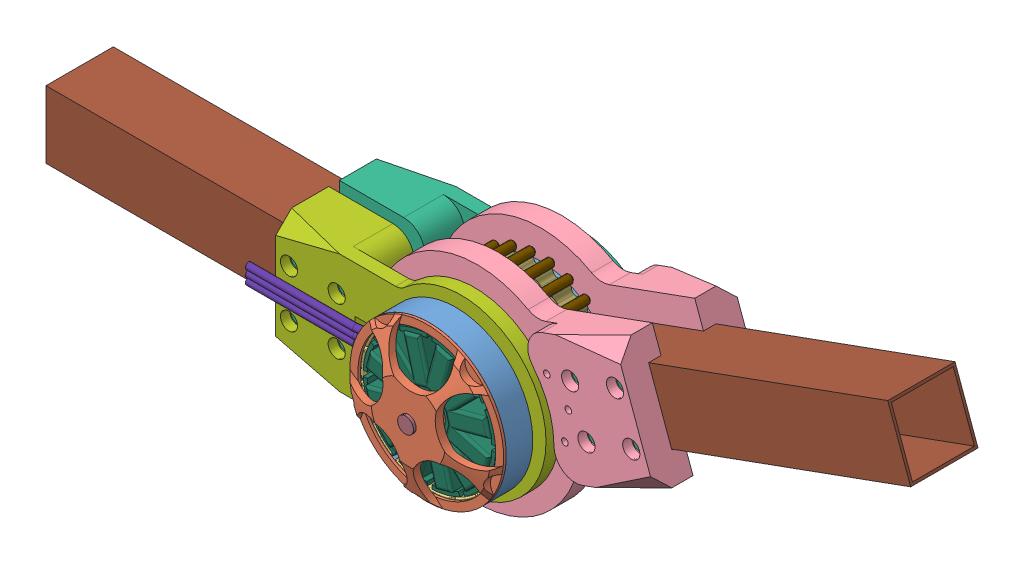
SolidWorks assembly hackaday, configuration Default. Lengths in mm.
Overall size (326.32 118.67 77).
127 component instances, 29 part files, 0 mates.
Components (placement in the parent):
- hackaday.stp-1: hackaday.stp [Default] at origin size (326.32 118.67 77)
  - 5008 motor.stp-1: 5008 motor.stp [Default] at (-7.1087 -103.7283 -19.7066) x (-0.351498 -0.936188 0) z (-0.936188 0.351498 0) size (59.12 18.06 59.12)
    - motor 5008 flux.stp-1: motor 5008 flux.stp [Default] at (33.74 9.1866 34) x (1 0 0) z (0 1 0) size (58 58 10)
    - motor 5008 top.stp-1: motor 5008 top.stp [Default] at (33.74 19.1866 34) size (59.12 8.62 59.12)
    - magnet 5008.stp-1: magnet 5008.stp [Default] at (33.74 19.1866 34) x (0.92388 0 0.382683) z (0 -1 0) size (10.37 4.02 10)
    - magnet 5008.stp-2: magnet 5008.stp [Default] at (33.74 19.1866 34) x (0.666347 0 0.745642) z (0 -1 0) size (10.37 4.02 10)
    - magnet 5008.stp-3: magnet 5008.stp [Default] at (33.74 19.1866 34) x (0.276836 0 0.960917) z (0 -1 0) size (10.37 4.02 10)
    - magnet 5008.stp-4: magnet 5008.stp [Default] at (33.74 19.1866 34) x (-0.167506 0 0.985871) z (0 -1 0) size (10.37 4.02 10)
    - magnet 5008.stp-5: magnet 5008.stp [Default] at (33.74 19.1866 34) x (-0.578671 0 0.815561) z (0 -1 0) size (10.37 4.02 10)
    - magnet 5008.stp-6: magnet 5008.stp [Default] at (33.74 19.1866 34) x (-0.875223 0 0.483719) z (0 -1 0) size (10.37 4.02 10)
    - magnet 5008.stp-7: magnet 5008.stp [Default] at (33.74 19.1866 34) x (-0.998427 0 0.05607) z (0 -1 0) size (10.37 4.02 10)
    - magnet 5008.stp-8: magnet 5008.stp [Default] at (33.74 19.1866 34) x (-0.92388 0 -0.382683) z (0 -1 0) size (10.37 4.02 10)
    - magnet 5008.stp-9: magnet 5008.stp [Default] at (33.74 19.1866 34) x (-0.666347 0 -0.745642) z (0 -1 0) size (10.37 4.02 10)
    - magnet 5008.stp-10: magnet 5008.stp [Default] at (33.74 19.1866 34) x (-0.276836 0 -0.960917) z (0 -1 0) size (10.37 4.02 10)
    - magnet 5008.stp-11: magnet 5008.stp [Default] at (33.74 19.1866 34) x (0.167506 0 -0.985871) z (0 -1 0) size (10.37 4.02 10)
    - magnet 5008.stp-12: magnet 5008.stp [Default] at (33.74 19.1866 34) x (0.578671 0 -0.815561) z (0 -1 0) size (10.37 4.02 10)
    - magnet 5008.stp-13: magnet 5008.stp [Default] at (33.74 19.1866 34) x (0.875223 0 -0.483719) z (0 -1 0) size (10.37 4.02 10)
    - magnet 5008.stp-14: magnet 5008.stp [Default] at (33.74 19.1866 34) x (0.998427 0 -0.05607) z (0 -1 0) size (10.37 4.02 10)
  - 6809_joint_out.stp-1: 6809_joint_out.stp [Default] at (-50.7987 -123.3644 -43.52) x (-0.34114 0.940012 0) z (0 0 -1) size (78 109 14)
  - 6809_joint_out.stp-2: 6809_joint_out.stp [Default] at (-50.7987 -123.3644 -25.52) x (0.34114 -0.940012 0) z (0 0 1) size (78 109 14)
  - 58x45x7_bearing.stp-1: 58x45x7_bearing.stp [Default] at (-50.7987 -123.3644 -18.52) x (1 0 0) z (0 0 -1) size (58 58 7)
  - 58x45x7_bearing.stp-2: 58x45x7_bearing.stp [Default] at (-50.7987 -123.3644 -43.52) x (1 0 0) z (0 0 -1) size (58 58 7)
  - encoder in 6809.stp-1: encoder in 6809.stp [Default] at (-50.7987 -123.3644 -42.52) x (1 0 0) z (0 0 -1) size (102 64 20)
  - motor in 6809.stp-1: motor in 6809.stp [Default] at (-50.7987 -123.3644 -26.52) size (102 64 20)
  - outer_bearing_holder.stp-1: outer_bearing_holder.stp [Default] at (-50.7987 -123.3644 -56.52) x (0 -1 0) z (0 0 -1) size (34 22 8)
  - enc_pcb.stp-1: enc_pcb.stp [Default] at (-50.7987 -123.3644 -53.52) x (1 0 0) z (0 0 -1) size (27 16 1.8)
  - enc_pcb.stp-2: enc_pcb.stp [Default] at (-50.7987 -123.3644 -58.32) x (1 0 0) z (0 0 -1) size (27 16 1.8)
  - magnet_holder.stp-1: magnet_holder.stp [Default] at (-50.7987 -123.3644 -65.52) x (0.34114 -0.940012 0) z (0 0 1) size (30 55 12)
  - bar25x25.stp-1: bar25x25.stp [Default] at (-11.3693 -108.8955 -34.52) x (0 0 -1) z (0.940012 0.34114 0) size (25.4 25.4 124)
  - bar25x25.stp-2: bar25x25.stp [Default] at (-92.7987 -123.2644 -34.52) x (0 0 1) z (-1 0 0) size (25.4 25.4 124)
  - inner_ring_25l.stp-1: inner_ring_25l.stp [Default] at (-50.111 -124.0904 -42.02) x (0.330465 0.943818 0) z (0 0 1) size (59.09 59.19 7)
  - inner_ring_25l.stp-2: inner_ring_25l.stp [Default] at (-51.4863 -122.6384 -27.02) x (-0.947128 0.320857 0) z (0 0 -1) size (59.09 59.19 7)
  - shaft_6mm.stp-1: shaft_6mm.stp [Default] at (-50.7987 -123.3644 -49.52) x (-0.834633 0.550807 0) z (0 0 1) size (6 6 58)
  - encoder_bearing_holder-45.stp-1: encoder_bearing_holder-45.stp [Default] at (-50.7987 -123.3644 -42.52) x (-1 0 0) z (0 0 -1) size (19 23.63 4)
  - motor 5008 stator.stp-1: motor 5008 stator.stp [Default] at (-50.7987 -123.3644 -0.52) x (1 0 0) z (0 0 -1) size (54.25 54.25 20.31)
  - sensor_cable.stp-1: sensor_cable.stp [Default] at (-130.7987 -126.7353 -57.155) x (1 0 0) z (0 1 0) size (67.53 3.96 7.65)
  - motor cable.stp-1: motor cable.stp [Default] at (-75.7987 -120.692 -13.5933) x (1 0 0) z (0 -1 0) size (54.18 4.8 7.51)
  - outer_pins.stp-1: outer_pins.stp [Default] at (-40.4962 -151.7528 -49.52) x (0.901282 0.433233 0) z (0 0 1) size (3.2 3.2 30)
  - outer_pins.stp-2: outer_pins.stp [Default] at (-47.5894 -153.3934 -49.52) x (0.978772 0.204953 0) z (0 0 1) size (3.2 3.2 30)
  - outer_pins.stp-3: outer_pins.stp [Default] at (-54.8691 -153.2888 -49.52) x (0.999379 -0.035238 0) z (0 0 1) size (3.2 3.2 30)
  - outer_pins.stp-4: outer_pins.stp [Default] at (-61.9122 -151.4452 -49.52) x (0.961906 -0.273381 0) z (0 0 1) size (3.2 3.2 30)
  - outer_pins.stp-5: outer_pins.stp [Default] at (-68.3094 -147.9696 -49.52) x (0.86853 -0.495637 0) z (0 0 1) size (3.2 3.2 30)
  - outer_pins.stp-6: outer_pins.stp [Default] at (-73.689 -143.064 -49.52) x (0.724679 -0.689087 0) z (0 0 1) size (3.2 3.2 30)
  - outer_pins.stp-7: outer_pins.stp [Default] at (-77.7382 -137.0136 -49.52) x (0.538711 -0.84249 0) z (0 0 1) size (3.2 3.2 30)
  - outer_pins.stp-8: outer_pins.stp [Default] at (-80.2219 -130.1699 -49.52) x (0.321436 -0.946931 0) z (0 0 1) size (3.2 3.2 30)
  - outer_pins.stp-9: outer_pins.stp [Default] at (-80.9955 -122.9307 -49.52) x (0.08548 -0.99634 0) z (0 0 1) size (3.2 3.2 30)
  - outer_pins.stp-10: outer_pins.stp [Default] at (-80.0143 -115.7167 -49.52) x (-0.155443 -0.987845 0) z (0 0 1) size (3.2 3.2 30)
  - outer_pins.stp-11: outer_pins.stp [Default] at (-77.3351 -108.9472 -49.52) x (-0.387333 -0.92194 0) z (0 0 1) size (3.2 3.2 30)
  - outer_pins.stp-12: outer_pins.stp [Default] at (-73.1137 -103.0155 -49.52) x (-0.596712 -0.802455 0) z (0 0 1) size (3.2 3.2 30)
  - outer_pins.stp-13: outer_pins.stp [Default] at (-67.5955 -98.2665 -49.52) x (-0.771413 -0.636335 0) z (0 0 1) size (3.2 3.2 30)
  - outer_pins.stp-14: outer_pins.stp [Default] at (-61.1011 -94.976 -49.52) x (-0.901282 -0.433233 0) z (0 0 1) size (3.2 3.2 30)
  - outer_pins.stp-15: outer_pins.stp [Default] at (-54.0079 -93.3354 -49.52) x (-0.978772 -0.204953 0) z (0 0 1) size (3.2 3.2 30)
  - outer_pins.stp-16: outer_pins.stp [Default] at (-46.7283 -93.44 -49.52) x (-0.999379 0.035238 0) z (0 0 1) size (3.2 3.2 30)
  - outer_pins.stp-17: outer_pins.stp [Default] at (-39.6852 -95.2836 -49.52) x (-0.961906 0.273381 0) z (0 0 1) size (3.2 3.2 30)
  - outer_pins.stp-18: outer_pins.stp [Default] at (-33.2879 -98.7592 -49.52) x (-0.86853 0.495637 0) z (0 0 1) size (3.2 3.2 30)
  - outer_pins.stp-19: outer_pins.stp [Default] at (-27.9084 -103.6648 -49.52) x (-0.724679 0.689087 0) z (0 0 1) size (3.2 3.2 30)
  - outer_pins.stp-20: outer_pins.stp [Default] at (-23.8591 -109.7153 -49.52) x (-0.538711 0.84249 0) z (0 0 1) size (3.2 3.2 30)
  - outer_pins.stp-21: outer_pins.stp [Default] at (-21.3754 -116.5589 -49.52) x (-0.321436 0.946931 0) z (0 0 1) size (3.2 3.2 30)
  - outer_pins.stp-22: outer_pins.stp [Default] at (-20.6018 -123.7981 -49.52) x (-0.08548 0.99634 0) z (0 0 1) size (3.2 3.2 30)
  - outer_pins.stp-23: outer_pins.stp [Default] at (-21.583 -131.0121 -49.52) x (0.155443 0.987845 0) z (0 0 1) size (3.2 3.2 30)
  - outer_pins.stp-24: outer_pins.stp [Default] at (-24.2622 -137.7816 -49.52) x (0.387333 0.92194 0) z (0 0 1) size (3.2 3.2 30)
  - outer_pins.stp-25: outer_pins.stp [Default] at (-28.4836 -143.7133 -49.52) x (0.596712 0.802455 0) z (0 0 1) size (3.2 3.2 30)
  - outer_pins.stp-26: outer_pins.stp [Default] at (-34.0018 -148.4623 -49.52) x (0.771413 0.636335 0) z (0 0 1) size (3.2 3.2 30)
  - inner_pins.stp-1: inner_pins.stp [Default] at (-70.2001 -131.4008 -20.52) x (1 0 0) z (0 0 -1) size (3 3 30)
  - inner_pins.stp-2: inner_pins.stp [Default] at (-70.2001 -115.3281 -20.52) x (0.707107 -0.707107 0) z (0 0 -1) size (3 3 30)
  - inner_pins.stp-3: inner_pins.stp [Default] at (-58.835 -103.9629 -20.52) x (0 -1 0) z (0 0 -1) size (3 3 30)
  - inner_pins.stp-4: inner_pins.stp [Default] at (-42.7623 -103.9629 -20.52) x (-0.707107 -0.707107 0) z (0 0 -1) size (3 3 30)
  - inner_pins.stp-5: inner_pins.stp [Default] at (-31.3972 -115.3281 -20.52) x (-1 0 0) z (0 0 -1) size (3 3 30)
  - inner_pins.stp-6: inner_pins.stp [Default] at (-31.3972 -131.4008 -20.52) x (-0.707107 0.707107 0) z (0 0 -1) size (3 3 30)
  - inner_pins.stp-7: inner_pins.stp [Default] at (-42.7623 -142.7659 -20.52) x (0 1 0) z (0 0 -1) size (3 3 30)
  - inner_pins.stp-8: inner_pins.stp [Default] at (-58.835 -142.7659 -20.52) x (0.707107 0.707107 0) z (0 0 -1) size (3 3 30)
  - 12x6x4 bearing.stp-1: 12x6x4 bearing.stp [Default] at (-50.7987 -123.3644 -46.52) size (12 12 4)
  - 18x12x4 bearing.stp-1: 18x12x4 bearing.stp [Default] at (-50.7987 -123.3644 -64.52) size (18 18 4)
  - 18x12x4 bearing.stp-2: 18x12x4 bearing.stp [Default] at (-50.111 -124.0904 -38.52) x (-0.944291 0.329113 0) z (0 0 -1) size (18 18 4)
  - 18x12x4 bearing.stp-3: 18x12x4 bearing.stp [Default] at (-50.111 -124.0904 -38.52) x (-0.863431 0.504468 0) z (0 0 1) size (18 18 4)
  - 18x12x4 bearing.stp-4: 18x12x4 bearing.stp [Default] at (-51.4863 -122.6384 -30.52) x (0.085182 -0.996365 0) z (0 0 1) size (18 18 4)
  - 18x12x4 bearing.stp-5: 18x12x4 bearing.stp [Default] at (-51.4863 -122.6384 -30.52) x (-0.162469 0.986714 0) z (0 0 -1) size (18 18 4)
  - 8x5x2_5 bearing.stp-1: 8x5x2_5 bearing.stp [Default] at (-44.4294 -103.8736 -41.02) x (-0.980599 0.196023 0) z (0 0 1) size (8 8 2.5)
  - 8x5x2_5 bearing.stp-2: 8x5x2_5 bearing.stp [Default] at (-31.7981 -113.8124 -41.02) x (-0.554779 0.831998 0) z (0 0 1) size (8 8 2.5)
  - 8x5x2_5 bearing.stp-3: 8x5x2_5 bearing.stp [Default] at (-29.8942 -129.772 -41.02) x (0.196023 0.980599 0) z (0 0 1) size (8 8 2.5)
  - 8x5x2_5 bearing.stp-4: 8x5x2_5 bearing.stp [Default] at (-39.833 -142.4033 -41.02) x (0.831998 0.554779 0) z (0 0 1) size (8 8 2.5)
  - 8x5x2_5 bearing.stp-5: 8x5x2_5 bearing.stp [Default] at (-55.7925 -144.3072 -41.02) x (0.980599 -0.196023 0) z (0 0 1) size (8 8 2.5)
  - 8x5x2_5 bearing.stp-6: 8x5x2_5 bearing.stp [Default] at (-68.4239 -134.3684 -41.02) x (0.554779 -0.831998 0) z (0 0 1) size (8 8 2.5)
  - 8x5x2_5 bearing.stp-7: 8x5x2_5 bearing.stp [Default] at (-70.3278 -118.4089 -41.02) x (-0.196023 -0.980599 0) z (0 0 1) size (8 8 2.5)
  - 8x5x2_5 bearing.stp-8: 8x5x2_5 bearing.stp [Default] at (-60.389 -105.7775 -41.02) x (-0.831998 -0.554779 0) z (0 0 1) size (8 8 2.5)
  - 8x5x2_5 bearing.stp-9: 8x5x2_5 bearing.stp [Default] at (-59.5854 -103.263 -31.02) x (-0.419199 0.907894 0) z (0 0 1) size (8 8 2.5)
  - 8x5x2_5 bearing.stp-10: 8x5x2_5 bearing.stp [Default] at (-70.9137 -114.6648 -31.02) x (-0.938397 0.34556 0) z (0 0 1) size (8 8 2.5)
  - 8x5x2_5 bearing.stp-11: 8x5x2_5 bearing.stp [Default] at (-70.8617 -130.7374 -31.02) x (-0.907894 -0.419199 0) z (0 0 1) size (8 8 2.5)
  - 8x5x2_5 bearing.stp-12: 8x5x2_5 bearing.stp [Default] at (-59.4599 -142.0658 -31.02) x (-0.34556 -0.938397 0) z (0 0 1) size (8 8 2.5)
  - 8x5x2_5 bearing.stp-13: 8x5x2_5 bearing.stp [Default] at (-43.3873 -142.0138 -31.02) x (0.419199 -0.907894 0) z (0 0 1) size (8 8 2.5)
  - 8x5x2_5 bearing.stp-14: 8x5x2_5 bearing.stp [Default] at (-32.059 -130.612 -31.02) x (0.938397 -0.34556 0) z (0 0 1) size (8 8 2.5)
  - 8x5x2_5 bearing.stp-15: 8x5x2_5 bearing.stp [Default] at (-32.111 -114.5394 -31.02) x (0.907894 0.419199 0) z (0 0 1) size (8 8 2.5)
  - 8x5x2_5 bearing.stp-16: 8x5x2_5 bearing.stp [Default] at (-43.5128 -103.211 -31.02) x (0.34556 0.938397 0) z (0 0 1) size (8 8 2.5)
  - offset 6id 12od.stp-1: offset 6id 12od.stp [Default] at (-50.7987 -123.3644 -42.52) x (-0.726007 -0.687687 0) z (0 0 1) size (12 14 16)
  - 12x6x4 bearing.stp-2: 12x6x4 bearing.stp [Default] at (-50.7987 -123.3644 -15.52) x (1 0 0) z (0 0 -1) size (12 12 4)
  - 12x6x4 bearing.stp-3: 12x6x4 bearing.stp [Default] at (-50.7987 -123.3644 -4.52) x (-0.950669 0.310208 0) z (0 0 1) size (12 12 4)
  - ANSI B18.3.5M - M3x6(1).stp-1: ANSI B18.3.5M - M3x6(1).stp [Default] at (-115.7987 -132.3644 -53.13) x (0 -1 0) z (0 0 -1) size (5.35 5.35 6)
  - ANSI B18.3.5M - M3x6(1).stp-2: ANSI B18.3.5M - M3x6(1).stp [Default] at (-115.7987 -114.3644 -53.13) x (0 -1 0) z (0 0 -1) size (5.35 5.35 6)
  - ANSI B18.3.5M - M3x6(1).stp-3: ANSI B18.3.5M - M3x6(1).stp [Default] at (-97.7987 -114.3644 -53.13) x (0 -1 0) z (0 0 -1) size (5.35 5.35 6)
  - ANSI B18.3.5M - M3x6(1).stp-4: ANSI B18.3.5M - M3x6(1).stp [Default] at (-97.7987 -132.3644 -53.13) x (0 -1 0) z (0 0 -1) size (5.35 5.35 6)
  - ANSI B18.3.5M - M3x6(1).stp-5: ANSI B18.3.5M - M3x6(1).stp [Default] at (-3.5478 -115.7909 -53.13) x (0.366871 -0.930272 0) z (0 0 -1) size (5.35 5.35 6)
  - ANSI B18.3.5M - M3x6(1).stp-6: ANSI B18.3.5M - M3x6(1).stp [Default] at (7.2319 -92.7302 -53.13) x (0.366871 -0.930272 0) z (0 0 -1) size (5.35 5.35 6)
  - ANSI B18.3.5M - M3x6(1).stp-7: ANSI B18.3.5M - M3x6(1).stp [Default] at (-9.6883 -98.8707 -53.13) x (0.366871 -0.930272 0) z (0 0 -1) size (5.35 5.35 6)
  - ANSI B18.3.5M - M3x6(1).stp-8: ANSI B18.3.5M - M3x6(1).stp [Default] at (13.3724 -109.6504 -53.13) x (0.366871 -0.930272 0) z (0 0 -1) size (5.35 5.35 6)
  - ANSI B18.3.5M - M3x6(1).stp-9: ANSI B18.3.5M - M3x6(1).stp [Default] at (-115.7987 -114.3644 -15.91) x (0 -1 0) z (0 0 1) size (5.35 5.35 6)
  - ANSI B18.3.5M - M3x6(1).stp-10: ANSI B18.3.5M - M3x6(1).stp [Default] at (-97.7987 -132.3644 -15.91) x (0 -1 0) z (0 0 1) size (5.35 5.35 6)
  - ANSI B18.3.5M - M3x6(1).stp-11: ANSI B18.3.5M - M3x6(1).stp [Default] at (-115.7987 -132.3644 -15.91) x (0 -1 0) z (0 0 1) size (5.35 5.35 6)
  - ANSI B18.3.5M - M3x6(1).stp-12: ANSI B18.3.5M - M3x6(1).stp [Default] at (-97.7987 -114.3644 -15.91) x (0 -1 0) z (0 0 1) size (5.35 5.35 6)
  - ANSI B18.3.5M - M3x6(1).stp-13: ANSI B18.3.5M - M3x6(1).stp [Default] at (-9.6883 -98.8707 -15.91) x (0.366871 -0.930272 0) z (0 0 1) size (5.35 5.35 6)
  - ANSI B18.3.5M - M3x6(1).stp-14: ANSI B18.3.5M - M3x6(1).stp [Default] at (13.3724 -109.6504 -15.91) x (0.366871 -0.930272 0) z (0 0 1) size (5.35 5.35 6)
  - ANSI B18.3.5M - M3x6(1).stp-15: ANSI B18.3.5M - M3x6(1).stp [Default] at (-3.5478 -115.7909 -15.91) x (0.366871 -0.930272 0) z (0 0 1) size (5.35 5.35 6)
  - ANSI B18.3.5M - M3x6(1).stp-16: ANSI B18.3.5M - M3x6(1).stp [Default] at (7.2319 -92.7302 -15.91) x (0.366871 -0.930272 0) z (0 0 1) size (5.35 5.35 6)
  - ANSI B18.3.1M - M2x0.4 x 10.stp-1: ANSI B18.3.1M - M2x0.4 x 10.stp [Default] at (-58.7987 -109.3644 -62.52) x (0 0 1) z (0 1 0) size (12 3.8 3.8)
  - ANSI B18.3.1M - M2x0.4 x 10.stp-2: ANSI B18.3.1M - M2x0.4 x 10.stp [Default] at (-42.7987 -109.3644 -62.52) x (0 0 1) z (0 1 0) size (12 3.8 3.8)
  - ANSI B18.3.1M - M2x0.4 x 10.stp-3: ANSI B18.3.1M - M2x0.4 x 10.stp [Default] at (-42.7987 -137.3644 -62.52) x (0 0 1) z (0 1 0) size (12 3.8 3.8)
  - ANSI B18.3.1M - M2x0.4 x 10.stp-4: ANSI B18.3.1M - M2x0.4 x 10.stp [Default] at (-58.7987 -137.3644 -62.52) x (0 0 1) z (0 1 0) size (12 3.8 3.8)
  - ANSI B18.3.1M - M2x0.4 x 10.stp-5: ANSI B18.3.1M - M2x0.4 x 10.stp [Default] at (-61.2987 -117.3644 -60.12) x (0 0 1) z (0 1 0) size (12 3.8 3.8)
  - ANSI B18.3.1M - M2x0.4 x 10.stp-6: ANSI B18.3.1M - M2x0.4 x 10.stp [Default] at (-40.2987 -129.3644 -60.12) x (0 0 1) z (0 1 0) size (12 3.8 3.8)
  - ANSI B18.3.1M - M2x0.4 x 10.stp-7: ANSI B18.3.1M - M2x0.4 x 10.stp [Default] at (-40.2987 -117.3644 -60.12) x (0 0 1) z (0 1 0) size (12 3.8 3.8)
  - ANSI B18.3.1M - M2x0.4 x 10.stp-8: ANSI B18.3.1M - M2x0.4 x 10.stp [Default] at (-61.2987 -129.3644 -60.12) x (0 0 1) z (0 1 0) size (12 3.8 3.8)
  - ANSI B18.6.7M - M3x0.5 x 4.stp-1: ANSI B18.6.7M - M3x0.5 x 4.stp [Default] at (-11.6668 -119.8012 -60.52) x (0 0 1) z (-0.366871 0.930272 0) size (6.38 5.6 5.6)
  - ANSI B18.6.7M - M3x0.5 x 4.stp-2: ANSI B18.6.7M - M3x0.5 x 4.stp [Default] at (-10.3781 -108.6954 -60.52) x (0 0 1) z (-0.366871 0.930272 0) size (6.38 5.6 5.6)
  - ANSI B18.6.7M - M3x0.5 x 4.stp-3: ANSI B18.6.7M - M3x0.5 x 4.stp [Default] at (-18.4896 -101.001 -60.52) x (0 0 1) z (-0.366871 0.930272 0) size (6.38 5.6 5.6)
  - 6mm diametric.stp-1: 6mm diametric.stp [Default] at (-50.7987 -123.3644 -62.02) x (0.866663 0.498894 0) z (0 0 -1) size (6 6 2)
  - motor_bearing_holder.stp-1: motor_bearing_holder.stp [Default] at (-50.7987 -123.3644 -47.52) x (1 0 0) z (0 0 -1) size (10 10 5)
  - 6mm diametric.stp-2: 6mm diametric.stp [Default] at (-50.7987 -123.3644 -51.02) x (1 0 0) z (0 0 -1) size (6 6 2)
  - silicon_steel.stp-1: silicon_steel.stp [Default] at (-55.2987 -117.3644 -56.32) x (1 0 0) z (0 0 -1) size (15 10 0.5)
